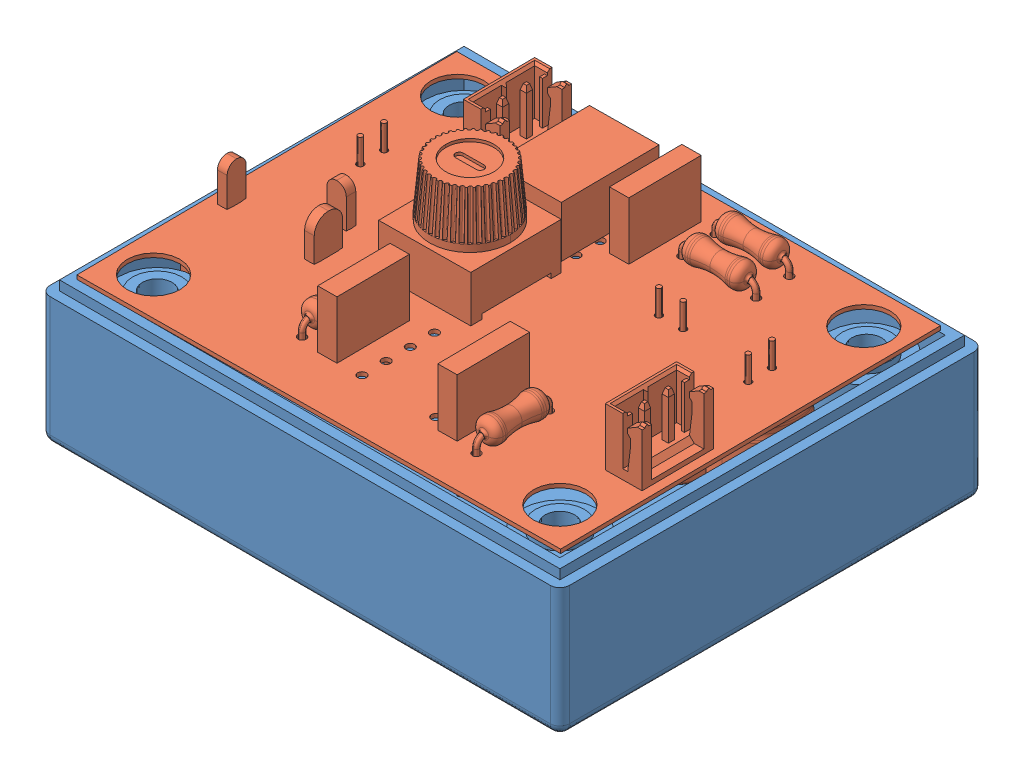
SolidWorks assembly Assemblage2, configuration Défaut. Lengths in mm.
Overall size (55.47 25.59 44.2).
2 component instances, 2 part files, 1 mates.
Components (placement in the parent):
- piècebas-1: piècebas [Défaut] at (-119.0188 32.6864 4.2569) size (54.2 14.5 44.2)
- carte_pcb.step-3: carte_pcb.step [Défaut] at (-141.9384 47.8645 19.3236) x (0.999958 0 -0.009212) z (0 1 0) size (53.04 40 22.42)
Mates (geometry in assembly coordinates):
- Coaxiale5: concentric anti-aligned: circle of piècebas-1; circle of carte_pcb.step-3
